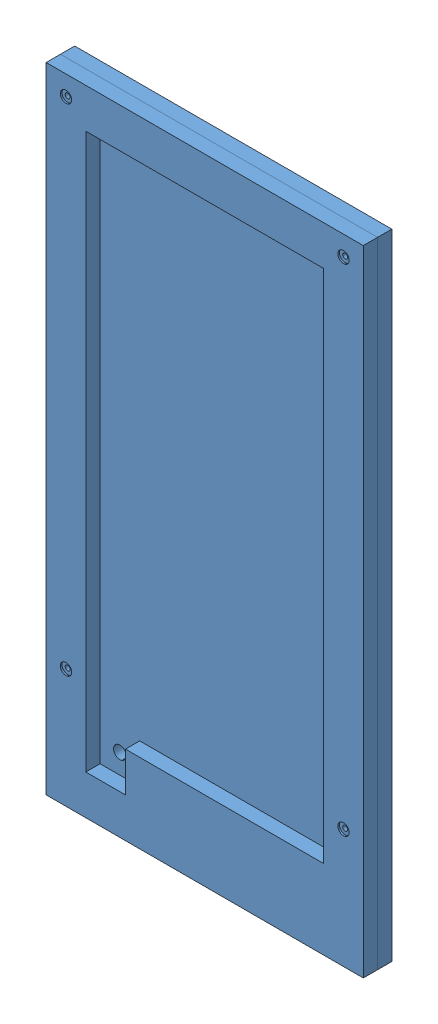
SolidWorks assembly bath, configuration Default. Lengths in mm.
Overall size (400 800 36).
3 component instances, 2 part files, 3 mates.
Components (placement in the parent):
- plate-1: plate [Bottom] at (-244.6378 -292.1937 11.5705) size (400 800 18)
- plate-2: plate [Top] at (-244.6378 -292.1937 29.5705) size (400 800 18)
- Part3^bath-1: Part3^bath [Default] at origin (virtual)
Mates (geometry in assembly coordinates):
- Coincident1: coincident aligned: plane of plate-1 through (-244.6378 507.8063 29.5705) normal (0 1 0); plane of plate-2 through (-244.6378 507.8063 47.5705) normal (0 1 0)
- Coincident2: coincident aligned: plane of plate-1 through (155.3622 -292.1937 29.5705) normal (1 0 0); plane of plate-2 through (155.3622 -292.1937 47.5705) normal (1 0 0)
- Coincident3: coincident anti-aligned: plane of plate-1 through (-244.6378 -292.1937 29.5705) normal (0 0 1); plane of plate-2 through (-244.6378 -292.1937 29.5705) normal (0 0 -1)
